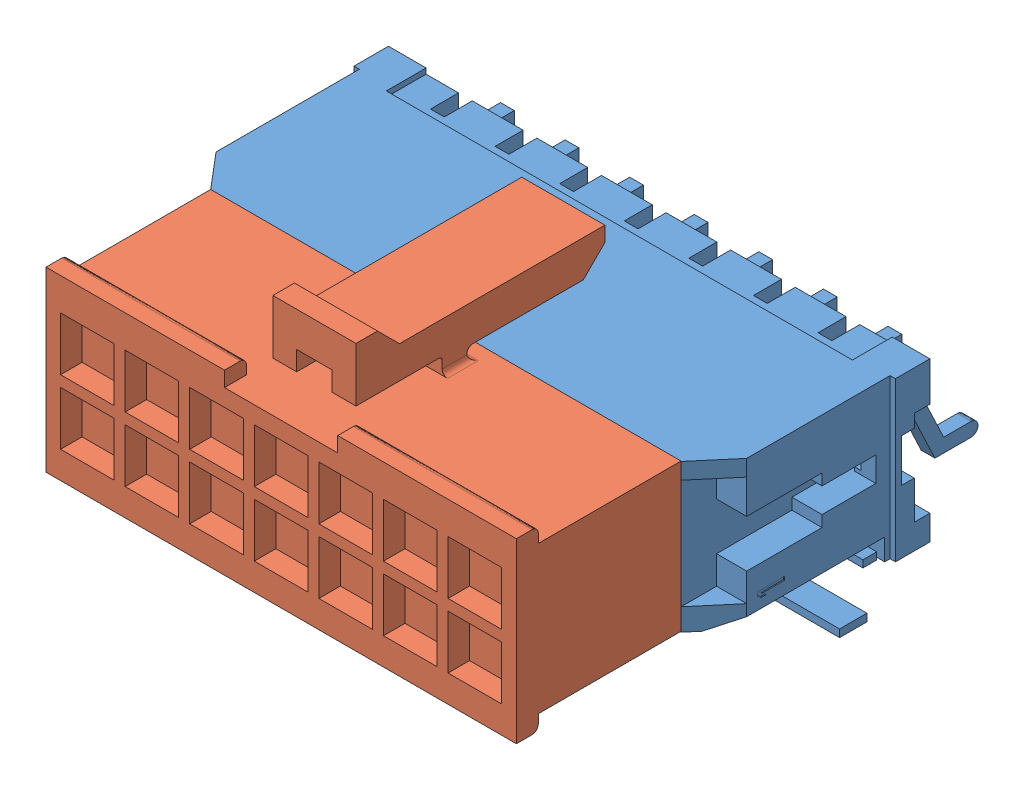
SolidWorks assembly Assem1, configuration Default. Lengths in mm.
Overall size (28.65 10.83 23.07).
2 component instances, 2 part files, 0 mates.
Components (placement in the parent):
- 430451409-1: 430451409 [Default] at (14.3316 16.1936 19.2281) size (28.65 8.77 15.4)
- 430251400-1: 430251400 [Default] at (14.3532 16.2513 27.857) x (-1 0 0) z (0 -1 0) size (21.85 14 10.83)
